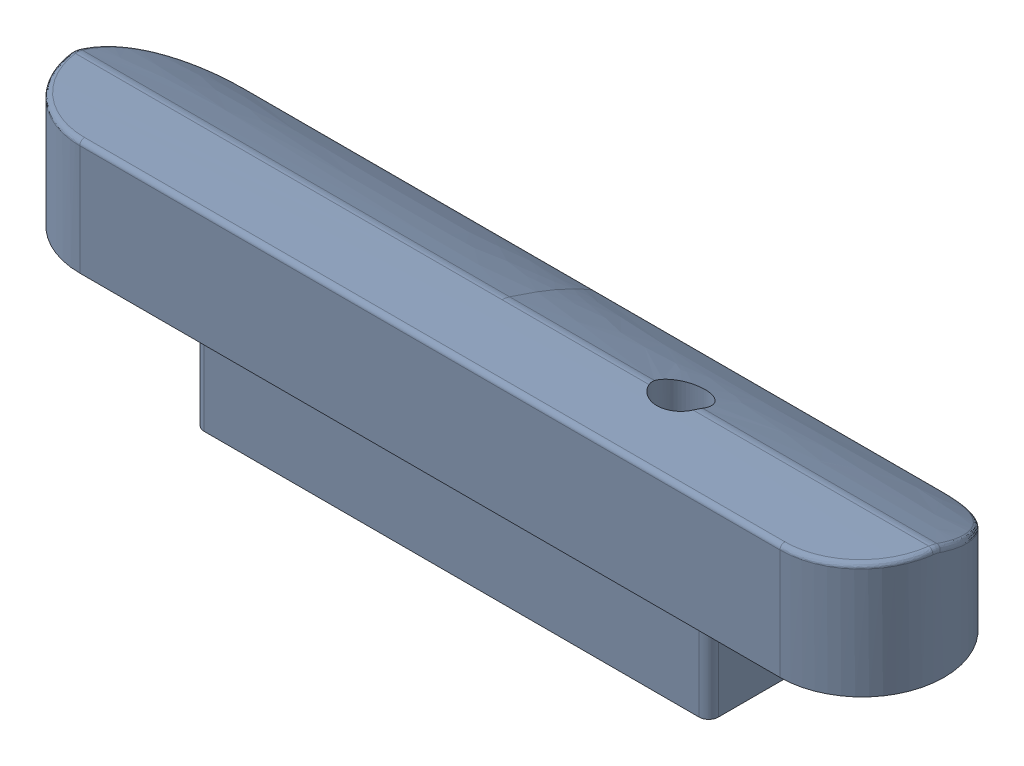
SolidWorks assembly AUX_COVER_SUBASSY_AWG_W_RGB_ASM_ASM, configuration Default. Lengths in mm.
Overall size (17.91 4.42 3.42).
3 component instances, 2 part files, 0 mates.
Components (placement in the parent):
- AUX_COVER_ALUMINUM_AWG_W_RGB_61-1: AUX_COVER_ALUMINUM_AWG_W_RGB_61 [Default] at origin size (17.91 4.42 3.42)
- PIN_STEEL_ZINC_PLATED_11-1: PIN_STEEL_ZINC_PLATED_11 [Default] at (7.25 10.95 -20.82) x (1 0 0) z (0 -1 0) size (1.6 1.6 1.6)
- PIN_STEEL_ZINC_PLATED_11-2: PIN_STEEL_ZINC_PLATED_11 [Default] at (-7.25 10.95 -20.82) x (1 0 0) z (0 -1 0) size (1.6 1.6 1.6)
